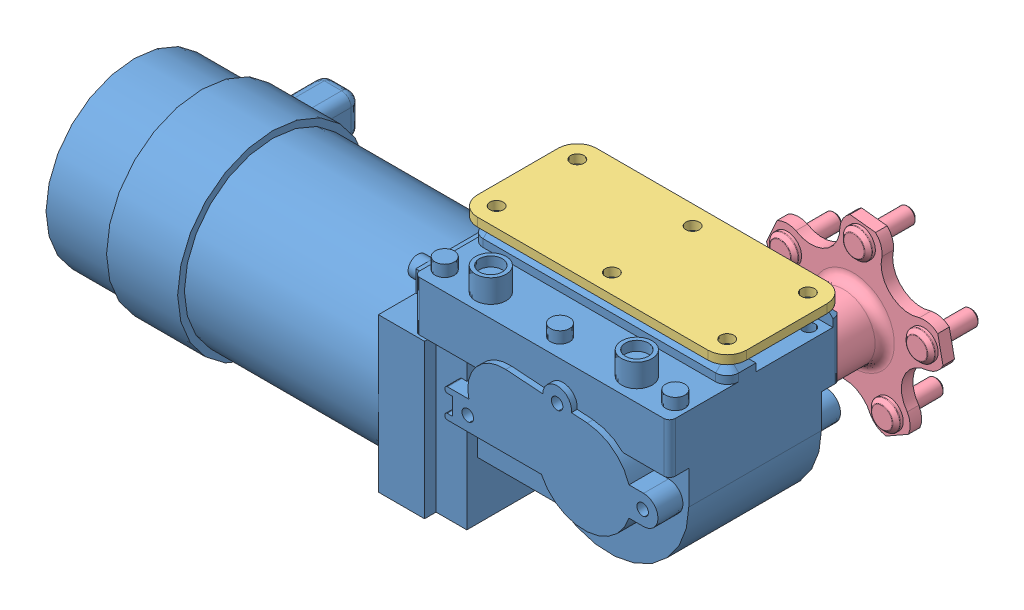
SolidWorks assembly motor assem, configuration Default. Lengths in mm.
4 component instances, 4 part files, 9 mates.
Components (placement in the parent):
- motor body-1: motor body [Default] at origin size (323 128 159)
- pin-1: pin [Default] at (0 -23.547 -79.7998) x (1 0 0) z (0 -1 0) size (6 40 6)
- connection plate-1: connection plate [Default] at (15.9331 20.25 -552.5501) size (140 4.5 62)
- Motor Coupler-1: Motor Coupler [Default] at (77.2002 -34.5 -63.8999) x (0.410997 0.911637 0) z (0 0 1) size (92.43 87.91 67)
Mates (geometry in assembly coordinates):
- Coincident1: coincident anti-aligned: plane of motor body-1 through (80.2002 -25.547 -19.8999) normal (-1 0 0); plane of pin-1 through (80.2002 -29.547 -22.8999) normal (1 0 0)
- Coincident2: coincident anti-aligned: plane of motor body-1 through (80.2002 -29.547 -19.8999) normal (0 1 0); plane of pin-1 through (77.2002 -29.547 -56.8999) normal (0 -1 0)
- Tangent1: tangent anti-aligned: plane of motor body-1 through (0 0 -19.8999) normal (0 0 -1); cylinder of pin-1 through (77.2002 -29.547 -22.8999) axis (0 1 0) radius 3
- Concentric1: concentric aligned: circle of motor body-1; circle of connection plate-1
- Coincident3: coordinate: point of motor body-1; point of assembly
- Concentric2: concentric anti-aligned: cylinder of motor body-1 through (-7.7998 3 42.6001) axis (0 1 0) radius 2.5; cylinder of connection plate-1 through (-7.7998 24.75 42.6001) axis (0 -1 0) radius 3.5
- Concentric30: concentric anti-aligned: cylinder of Motor Coupler-1 through (77.2002 -34.5 -20.9899) axis (0 0 -1) radius 8.5; cylinder of motor body-1 through (77.2002 -34.5 -61.8999) axis (0 0 1) radius 8.5
- Coincident58: coincident anti-aligned: plane of Motor Coupler-1 through (77.2002 -34.5 -15.8999) normal (0 0 1); plane of motor body-1 through (77.2002 -34.5 -15.8999) normal (0 0 -1)
- Coincident59: coincident anti-aligned: plane of motor body-1 through (-8.2998 17 43.1001) normal (0 1 0); plane of connection plate-1 through (-7.7998 17 42.6001) normal (0 -1 0)
